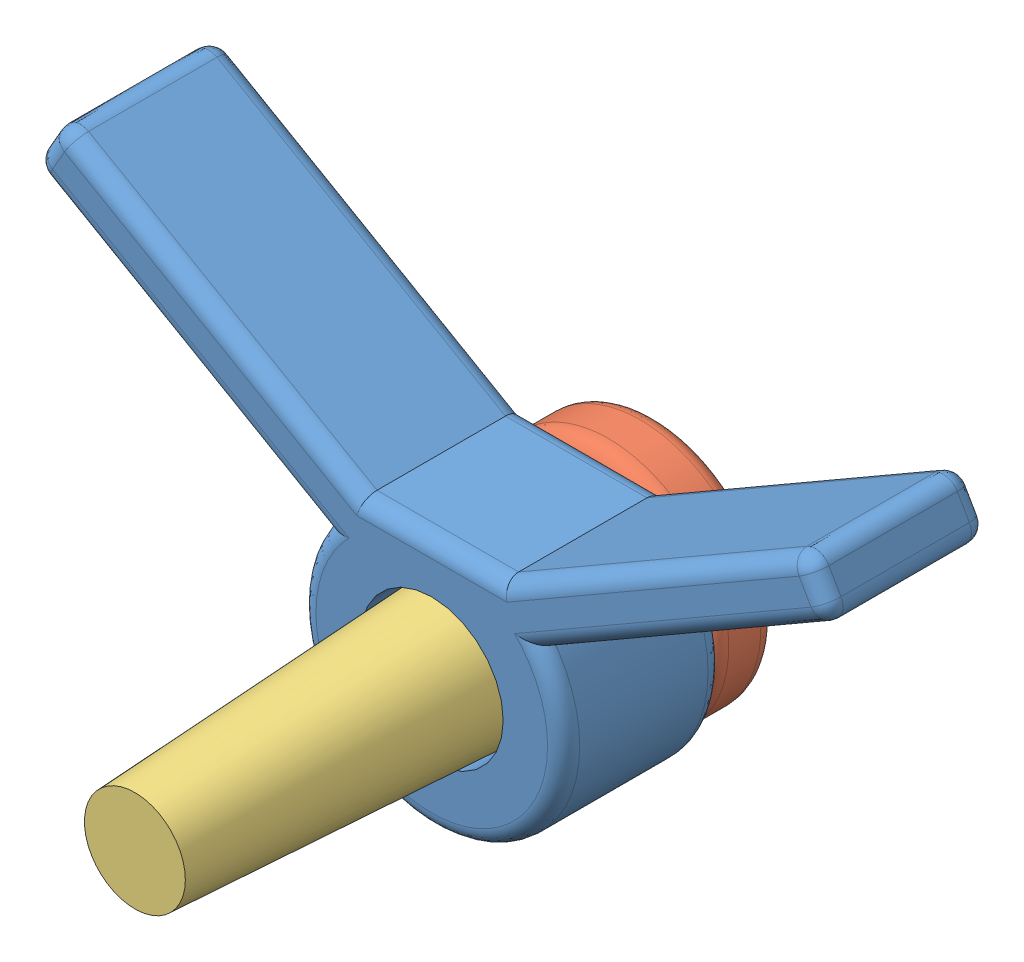
SolidWorks assembly armRest3assem, configuration Default. Lengths in mm.
Overall size (125.14 66.62 82.55).
3 component instances, 3 part files, 2 mates.
Components (placement in the parent):
- armRest3-1: armRest3 [Default] at (-39.6556 17.54 -5.5867) size (125.14 66.62 25.87)
- StabWght1-1: StabWght1 [Default] at (-39.6556 7.8904 -15.7467) size (38.1 38.1 10.16)
- bowSide2-1: bowSide2 [Default] at (-39.6556 7.8904 -15.7467) size (22.23 22.23 82.55)
Mates (geometry in assembly coordinates):
- Coincident2: coincident aligned: circle of armRest3-1; circle of StabWght1-1
- Coincident3: coincident aligned: circle of armRest3-1; circle of bowSide2-1
